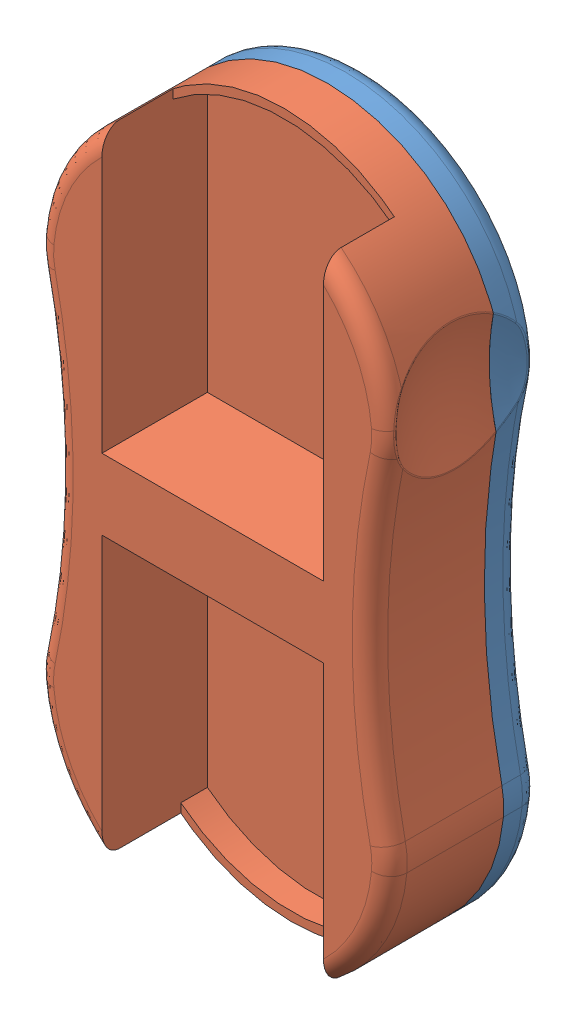
SolidWorks assembly Assem1, configuration Default. Lengths in mm.
Overall size (40.22 80 17.16).
2 component instances, 2 part files, 3 mates.
Components (placement in the parent):
- General Shape Lower Half-1: General Shape Lower Half [Default] at (-4.6455 83.5723 66.989) size (40.14 80 4.1)
- General Shape Upper Half-1: General Shape Upper Half [Default] at (-4.6455 83.5723 66.989) size (40 80 13.06)
Mates (geometry in assembly coordinates):
- Coincident1: coincident: circle of General Shape Lower Half-1; circle of General Shape Upper Half-1
- Coincident2: coincident: plane of General Shape Lower Half-1 through (-24.6045 8.5723 71.089) normal (0 0 1); plane of General Shape Upper Half-1 through (-4.6455 94.5723 71.089) normal (0 0 -1)
- Coincident3: coincident anti-aligned: circle of General Shape Lower Half-1; circle of General Shape Upper Half-1
